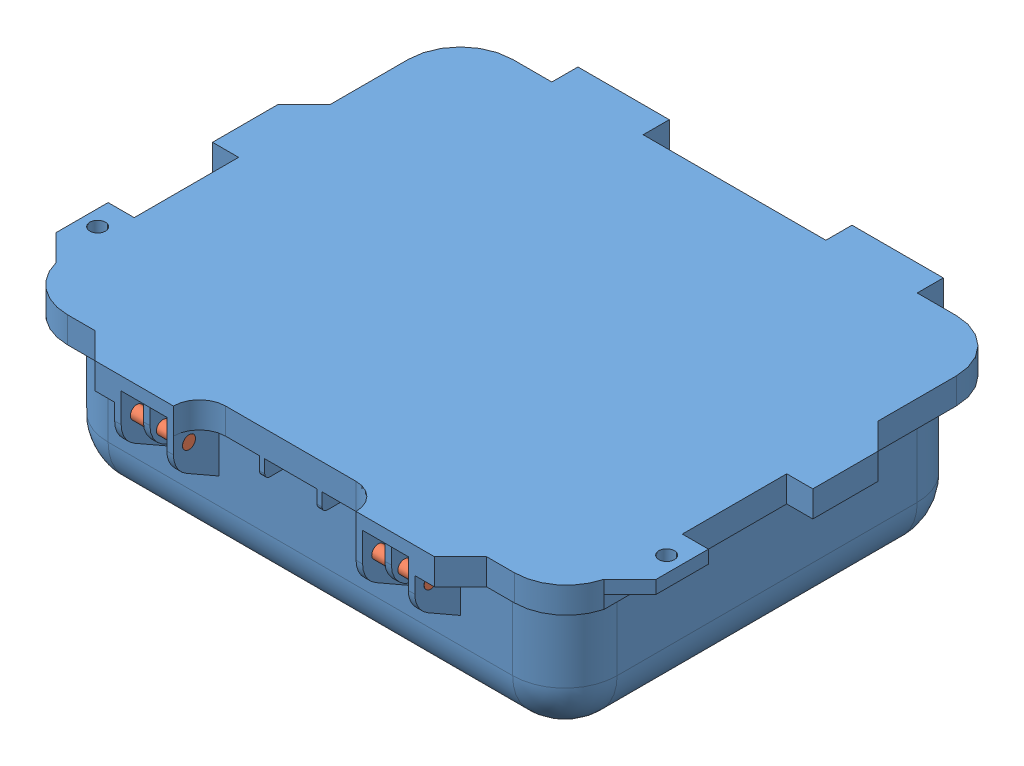
SolidWorks assembly container, configuration Default. Lengths in mm.
Overall size (292.1 85.09 238.13).
3 component instances, 2 part files, 6 mates.
Components (placement in the parent):
- container main-1: container main [Default] at origin size (292.1 85.09 238.13)
- front handle pin-1: front handle pin [Default] at (-58.801 -6.35 113.03) size (28.7 6.35 6.35)
- front handle pin-2: front handle pin [Default] at (58.801 -6.35 113.03) size (28.7 6.35 6.35)
Mates (geometry in assembly coordinates):
- Coincident1: coincident: axis of container main-1 through (-57.15 -6.35 113.03) axis (-1 0 0); axis of front handle pin-1 through (-44.45 -6.35 113.03) axis (-1 0 0)
- Coincident2: coincident: plane of container main-1 through (-44.45 10.16 120.65) normal (1 0 0); plane of front handle pin-1 through (-44.45 -6.35 113.03) normal (1 0 0)
- Parallel1: parallel: plane of container main-1 through (0 0 0) normal (0 0 1); plane of front handle pin-1 through (-58.801 -6.35 113.03) normal (0 0 1)
- Coincident4: coincident: axis of container main-1 through (57.15 -6.35 113.03) axis (1 0 0); axis of front handle pin-2 through (73.152 -6.35 113.03) axis (-1 0 0)
- Coincident5: coincident: plane of container main-1 through (44.45 10.16 120.65) normal (-1 0 0); plane of front handle pin-2 through (44.45 -6.35 113.03) normal (-1 0 0)
- Parallel2: parallel: plane of container main-1 through (0 0 0) normal (0 0 1); plane of front handle pin-2 through (58.801 -6.35 113.03) normal (0 0 1)
